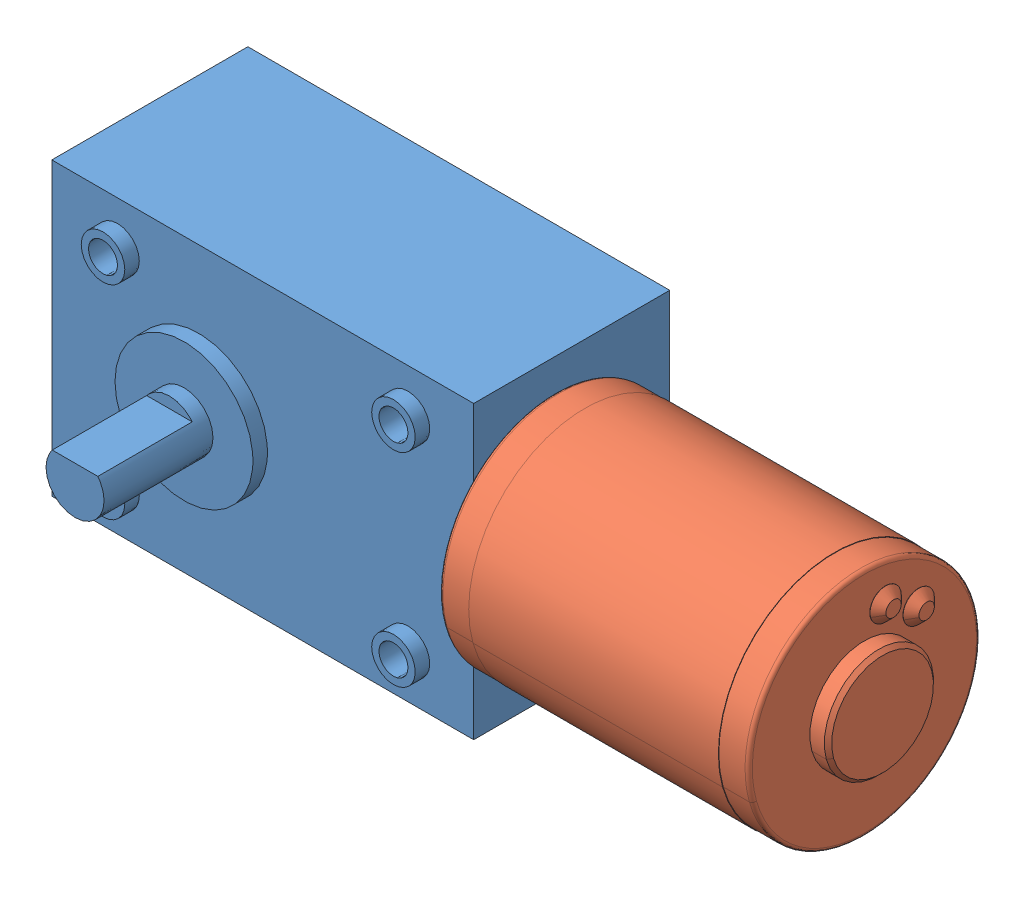
SolidWorks assembly gearbox_motor_assem, configuration Default. Lengths in mm.
Overall size (103.21 40.11 47.92).
2 component instances, 2 part files, 5 mates.
Components (placement in the parent):
- gearbox-1: gearbox [Default] at (-16.8719 -24.4163 -25.4632) size (58.1 40.11 44)
- Mini_CIM_Motor_217-3371-1: Mini_CIM_Motor_217-3371 [Default] at (19.8669 -4.4211 -9.6623) x (1 0 0) z (0 -0.269049 0.963126) size (62.91 32 32)
Mates (geometry in assembly coordinates):
- Concentric1: concentric aligned: cylinder of gearbox-1 through (15.8281 -4.4163 -9.6653) axis (1 0 0) radius 4; cylinder of Mini_CIM_Motor_217-3371-1 through (41.2281 -4.4163 -9.6653) axis (1 0 0) radius 2
- Coincident1: coincident anti-aligned: plane of gearbox-1 through (41.2281 -24.4163 1.5368) normal (1 0 0); plane of Mini_CIM_Motor_217-3371-1 through (41.2281 0.1705 -8.3839) normal (-1 0 0)
- Concentric2: concentric anti-aligned: cylinder of gearbox-1 through (32.1781 9.6387 -4.4632) axis (0 0 1) radius 2; cylinder of motor_mount_-1 through (32.1781 9.6387 6.5368) axis (0 0 -1) radius 2
- Concentric3: concentric anti-aligned: cylinder of gearbox-1 through (-7.8219 9.6387 -4.4632) axis (0 0 1) radius 2; cylinder of motor_mount_-1 through (-7.8219 9.6387 6.5368) axis (0 0 -1) radius 2
- Coincident2: coincident anti-aligned: plane of gearbox-1 through (3.3281 -4.3613 3.5368) normal (0 0 1); plane of motor_mount_-1 through (-11.8219 -36.3613 3.5368) normal (0 0 -1)
